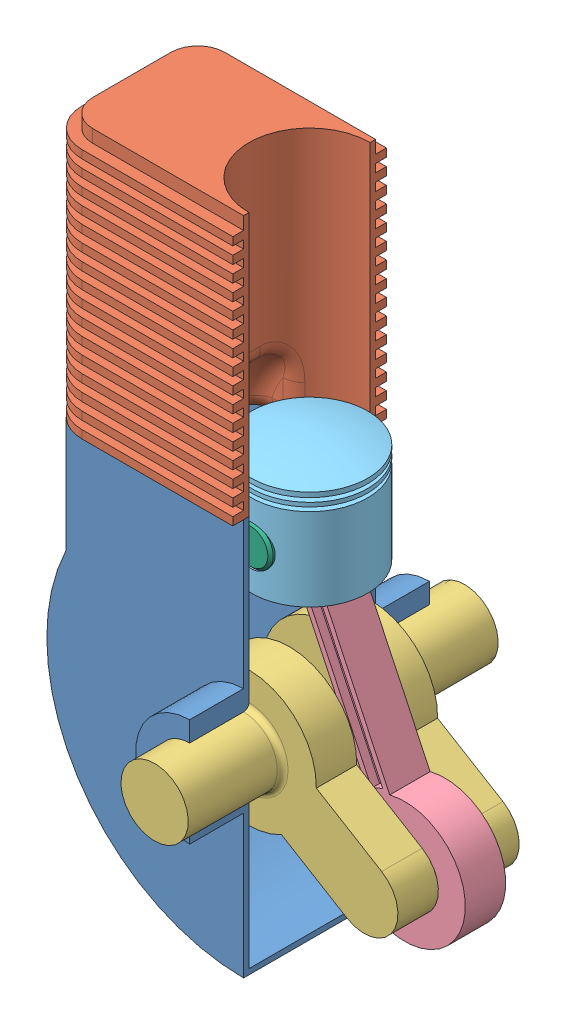
SolidWorks assembly MOTOR_PARCA_BİLEŞİMİ, configuration Varsayılan. Lengths in mm.
Overall size (145.76 245.01 115).
6 component instances, 6 part files, 13 mates.
Components (placement in the parent):
- ALT KARTEL-1: ALT KARTEL [Varsayılan] at (-63.4939 59.7553 147.2563) size (73 147.26 89)
- ÜST KAPAK-1: ÜST KAPAK [Varsayılan] at (-30.5089 108.6303 147.2563) size (69.97 97.75 57)
- KRANK-1: KRANK [Varsayılan] at (2.4761 -14.501 154.7563) x (-0.517089 -0.855932 0) z (0 0 1) size (50 87.5 115)
- BİLEY-1: BİLEY [Varsayılan] at (33.8773 -10.9407 147.2563) x (0.903795 0.427966 0) z (0 0 1) size (45 133 15)
- PİSTON-1: PİSTON [Varsayılan] at (2.4761 34.6876 147.2563) size (43.16 40 43.16)
- PİN-1: PİN [Varsayılan] at (2.4761 50.024 125.2563) size (15 15 44)
Mates (geometry in assembly coordinates):
- Coincident6: coincident: point of ALT KARTEL-1; point of ÜST KAPAK-1
- Concentric1: concentric aligned: cylinder of ALT KARTEL-1 through (2.4761 -14.501 171.7563) axis (0 0 -1) radius 12.5; cylinder of KRANK-1 through (2.4761 -14.501 204.7563) axis (0 0 -1) radius 12.5
- Width1: width anti-aligned: plane of ALT KARTEL-1 through (2.4761 -14.501 124.7563) normal (0 0 1); plane of KRANK-1 through (2.4761 -14.501 169.7563) normal (0 0 -1); plane of ALT KARTEL-1 through (2.4851 35.499 124.7563) normal (0 0 -1); plane of KRANK-1 through (2.4851 35.499 169.7563) normal (0 0 1)
- Concentric2: concentric anti-aligned: cylinder of KRANK-1 through (2.4851 35.499 139.7563) axis (0 0 1) radius 10; cylinder of BİLEY-1 through (2.4851 35.499 154.7563) axis (0 0 -1) radius 12.5
- Width2: width aligned: plane of KRANK-1 through (2.4851 35.499 139.7563) normal (0 0 1); plane of BİLEY-1 through (2.4851 35.499 154.7563) normal (0 0 -1); plane of KRANK-1 through (2.4851 35.499 154.7563) normal (0 0 1); plane of BİLEY-1 through (2.4851 35.499 139.7563) normal (0 0 -1)
- Concentric3: concentric aligned: circle of BİLEY-1; cylinder of PİSTON-1 through (2.4761 135.499 122.7563) axis (0 0 1) radius 7.5
- Width3: width anti-aligned: plane of PİSTON-1 through (2.4761 120.1626 139.7563) normal (0 0 1); plane of BİLEY-1 through (2.4761 120.1626 154.7563) normal (0 0 -1); plane of PİSTON-1 through (2.4851 35.499 139.7563) normal (0 0 -1); plane of BİLEY-1 through (2.4851 35.499 154.7563) normal (0 0 1)
- Concentric4: concentric anti-aligned: cylinder of PİSTON-1 through (2.4761 135.499 122.7563) axis (0 0 1) radius 7.5; cylinder of PİN-1 through (2.4761 135.499 169.2563) axis (0 0 -1) radius 7.5
- Width4: width aligned: plane of BİLEY-1 through (2.4851 35.499 154.7563) normal (0 0 1); plane of PİN-1 through (2.4851 35.499 139.7563) normal (0 0 -1); plane of BİLEY-1 through (2.4761 135.499 169.2563) normal (0 0 1); plane of PİN-1 through (2.4761 135.499 125.2563) normal (0 0 -1)
- Concentric6: concentric anti-aligned: cylinder of ÜST KAPAK-1 through (2.4761 -3.8843 147.2563) axis (0 1 0) radius 22.5; cylinder of PİSTON-1 through (2.4761 120.1626 147.2563) axis (0 -1 0) radius 21.5812
- Parallel1: parallel aligned: line of ALT KARTEL-1 through (-63.4939 59.7553 171.7563) axis (0 0 -1); line of ÜST KAPAK-1 through (-67.4939 59.7553 161.7563) axis (0 0 -1)
- Parallel2: parallel aligned: line of ALT KARTEL-1 through (-63.4939 59.7553 171.7563) axis (0 0 -1); line of ÜST KAPAK-1 through (-63.4939 157.5053 161.7563) axis (0 0 -1)
- Tangent1: tangent: plane of ALT KARTEL-1 through (-63.4939 59.7553 171.7563) normal (-1 0 0); circle of ÜST KAPAK-1
